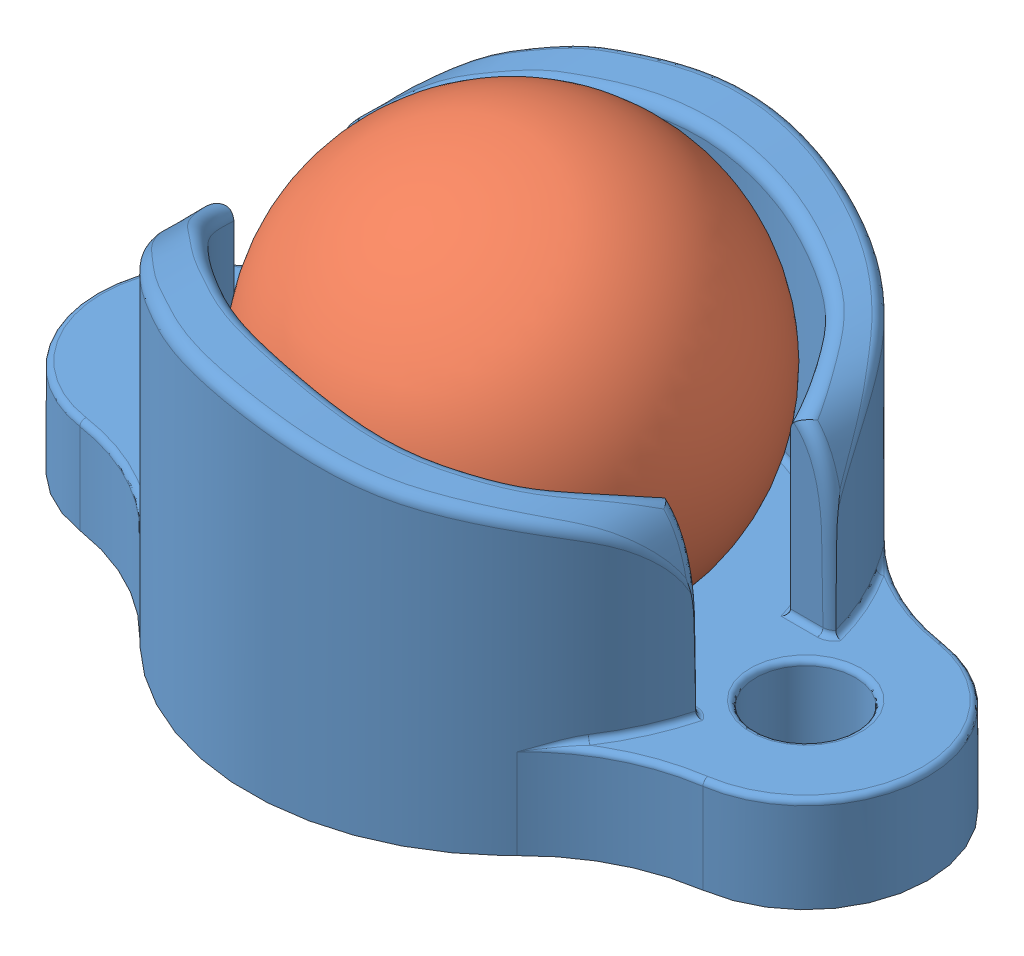
SolidWorks assembly Pololu Ball Caster, configuration Predeterminado. Lengths in mm.
Overall size (19.05 10.36 12.25).
2 component instances, 2 part files, 2 mates.
Components (placement in the parent):
- base-1: base [Predeterminado] at origin size (19.05 8.14 12.25)
- ball-1: ball [Predeterminado] at (0 4.4161 0) x (0.999099 0.024067 0.034961) z (-0.035416 0.018735 0.999197) size (9.3 9.3 9.3)
Mates (geometry in assembly coordinates):
- Concéntrica1: concentric: cylinder of base-1 through (0 1.0939 0) axis (0 -1 0) radius 2.856; sphere of ball-1
- Tangente2: tangent: unknown of ball-1
